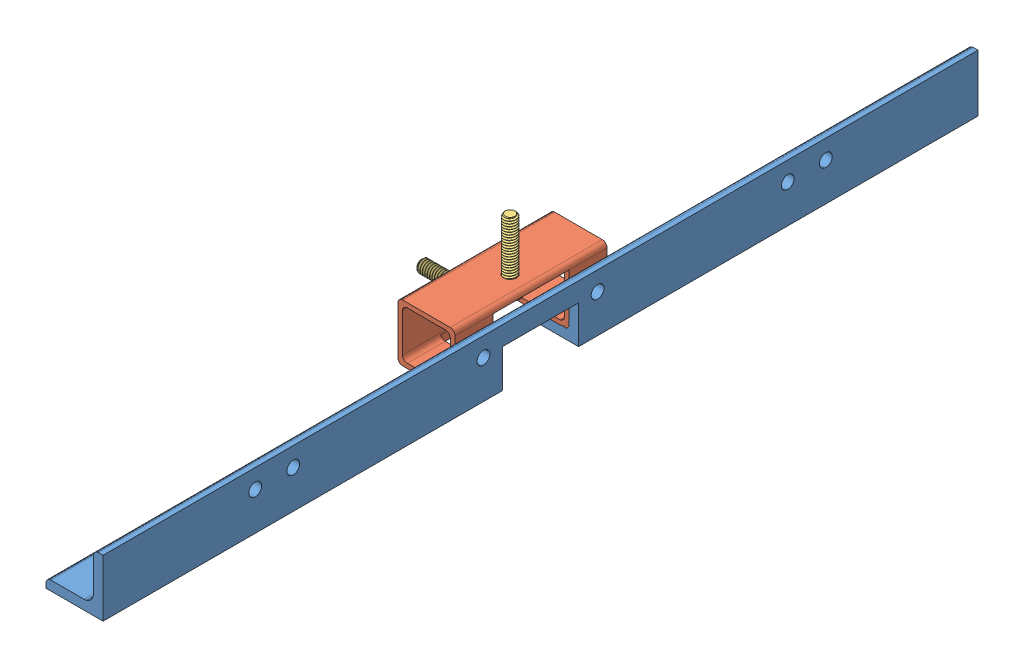
SolidWorks assembly Counterweight bracket, configuration Default. Lengths in mm.
Overall size (40.16 40.16 292.1).
4 component instances, 3 part files, 8 mates.
Components (placement in the parent):
- L_Bar-1: L_Bar [8982K281] at (113.5769 157.021 218.6975) size (19.05 19.05 292.1)
- Square Tube-1: Square Tube [6546K522] at (110.4019 160.196 218.6975) x (0 -1 0) z (0 0 1) size (19.05 19.05 50.8)
- .75 L 8-32 cap screw-1: .75 L 8-32 cap screw [90128A197] at (112.9419 175.6392 218.6975) x (1 0 0) z (0 -1 0) size (6.87 6.87 23.83)
- .75 L 8-32 cap screw-2: .75 L 8-32 cap screw [90128A197] at (94.9587 157.656 218.6975) x (0 1 0) z (1 0 0) size (6.87 6.87 23.83)
Mates (geometry in assembly coordinates):
- Coincident4: coincident anti-aligned: plane of L_Bar-1 through (119.9269 164.9585 364.7475) normal (-1 0 0); plane of Square Tube-1 through (119.9269 169.721 244.0975) normal (1 0 0)
- Coincident5: coincident anti-aligned: plane of L_Bar-1 through (116.7519 150.671 364.7475) normal (0 1 0); plane of Square Tube-1 through (100.8769 150.671 244.0975) normal (0 -1 0)
- Coincident7: coincident anti-aligned: circle of L_Bar-1; circle of Square Tube-1
- Coincident8: coincident anti-aligned: circle of L_Bar-1; circle of Square Tube-1
- Coincident9: coincident anti-aligned: circle of Square Tube-1; plane of .75 L 8-32 cap screw-1 through (112.9419 168.197 220.7803) normal (0 1 0)
- Coincident10: coincident anti-aligned: circle of Square Tube-1; plane of .75 L 8-32 cap screw-2 through (102.4009 157.656 220.7803) normal (-1 0 0)
- Concentric1: concentric aligned: circle of Square Tube-1; circle of .75 L 8-32 cap screw-2
- Concentric2: concentric aligned: circle of Square Tube-1; circle of .75 L 8-32 cap screw-1
